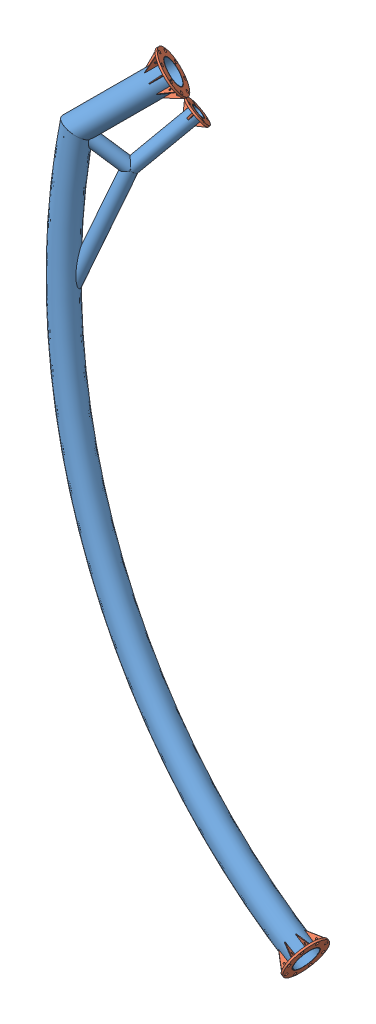
SolidWorks assembly pipe_a_asm, configuration Default. Lengths in mm.
Overall size (5133.88 5119.61 3952.51).
4 component instances, 2 part files, 6 mates.
Components (placement in the parent):
- pipe_curve^pipe_a_asm-1: pipe_curve^pipe_a_asm [Default<As Machined>] at origin size (5133.88 5119.61 3952.51) (virtual)
- pipe_flange-3: pipe_flange [Default] at (-709.2559 456.6722 2971.914) x (-0.543791 0.80573 0.234711) z (-0.559162 -0.556417 0.614604) size (279.4 279.4 111.05)
- pipe_flange-4: pipe_flange [Sch40_3_inch] at (-630.7864 218.7903 2881.7665) x (-0.248326 0.787094 0.564639) z (-0.388301 -0.614899 0.686383) size (177.8 177.8 57.15)
- pipe_flange-2: pipe_flange [Default] at (1016.6393 -3466.0879 3799.6778) x (-0.030467 -0.177517 -0.983646) z (-0.890523 0.45173 -0.05394) size (279.4 279.4 111.05)
Mates (geometry in assembly coordinates):
- Coincident8: coincident aligned: plane of pipe_curve^pipe_a_asm-1 through (-630.7864 218.7903 2881.7665) normal (0.388301 0.614899 -0.686383); plane of pipe_flange-4 through (-630.7864 218.7903 2881.7665) normal (0.388301 0.614899 -0.686383)
- Concentric5: concentric aligned: cylinder of pipe_curve^pipe_a_asm-1 through (-796.9754 -44.3808 3175.5317) axis (0.388301 0.614899 -0.686383) radius 44.45; cylinder of pipe_flange-4 through (-635.7178 210.981 2890.4836) axis (0.388301 0.614899 -0.686383) radius 44.45
- Concentric9: concentric anti-aligned: circle of pipe_curve^pipe_a_asm-1; circle of pipe_flange-2
- Coincident41: coincident aligned: plane of pipe_curve^pipe_a_asm-1 through (-709.2559 456.6722 2971.914) normal (0.559162 0.556417 -0.614604); plane of pipe_flange-3 through (-709.2559 456.6722 2971.914) normal (0.559162 0.556417 -0.614604)
- Concentric10: concentric aligned: circle of pipe_curve^pipe_a_asm-1; circle of pipe_flange-3
- Coincident42: coincident aligned: plane of pipe_curve^pipe_a_asm-1 through (1016.6393 -3466.0879 3799.6778) normal (0.890523 -0.45173 0.05394); plane of pipe_flange-2 through (1016.6393 -3466.0879 3799.6778) normal (0.890523 -0.45173 0.05394)
